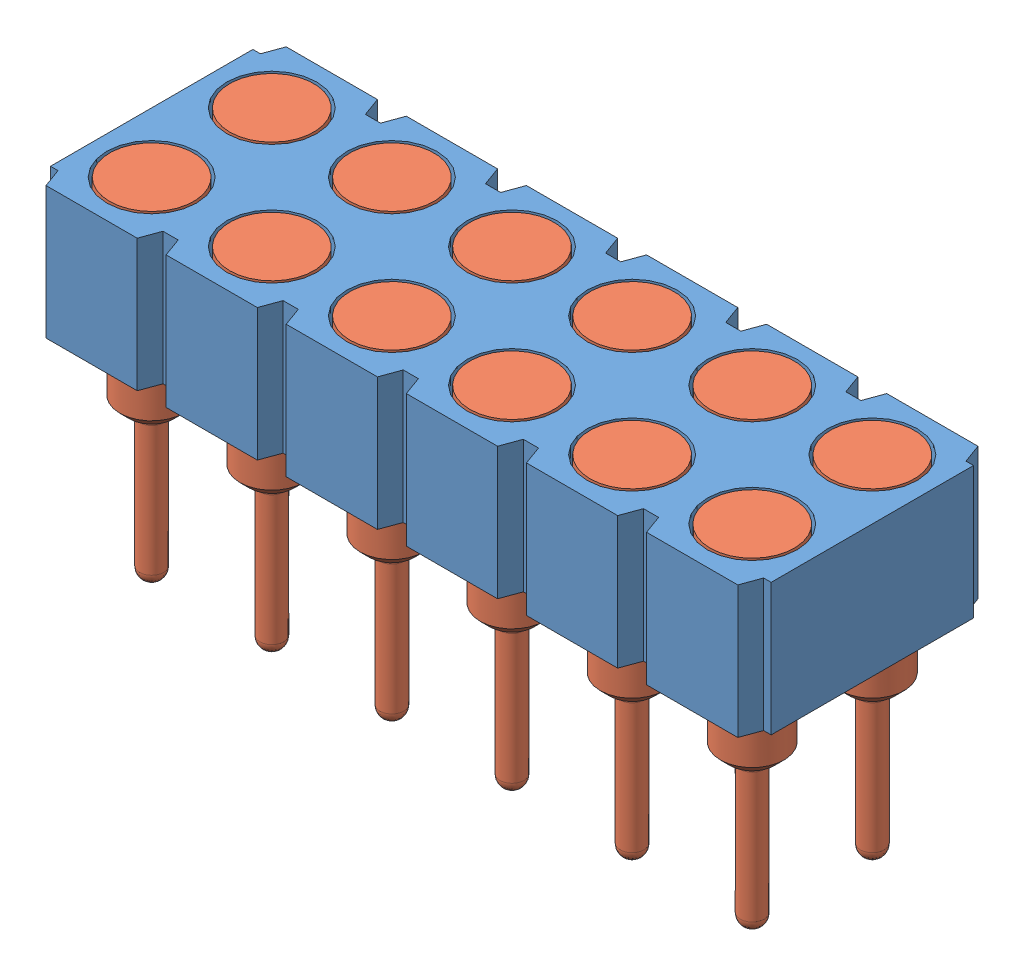
SolidWorks assembly mill-max-419-10-212-00-001000, configuration MillMaxsldprt2015419-XX-XXX-00-0010001210uGoldoverNickelPage14off. Lengths in mm.
Overall size (15.24 7.37 5.08).
13 component instances, 2 part files, 4 mates.
Components (placement in the parent):
- mill-max-419-10-212-00-001000_P4XX-21-010-00-000000-1: mill-max-419-10-212-00-001000_P4XX-21-010-00-000000 [P412-21-010-00-000000] at origin size (15.24 2.79 5.08)
- mill-max-419-10-212-00-001000_1942-1: mill-max-419-10-212-00-001000_1942 [Default] at (0.9644 0 -1.27) x (0 -1 0) z (0 0 1) size (7.37 1.78 1.78)
- mill-max-419-10-212-00-001000_1942-31: mill-max-419-10-212-00-001000_1942 [Default] at (0.9644 0 -3.81) x (0 -1 0) z (0 0 1) size (7.37 1.78 1.78)
- mill-max-419-10-212-00-001000_1942-32: mill-max-419-10-212-00-001000_1942 [Default] at (3.5044 0 -3.81) x (0 -1 0) z (0 0 1) size (7.37 1.78 1.78)
- mill-max-419-10-212-00-001000_1942-20: mill-max-419-10-212-00-001000_1942 [Default] at (3.5044 0 -1.27) x (0 -1 0) z (0 0 1) size (7.37 1.78 1.78)
- mill-max-419-10-212-00-001000_1942-33: mill-max-419-10-212-00-001000_1942 [Default] at (6.0444 0 -3.81) x (0 -1 0) z (0 0 1) size (7.37 1.78 1.78)
- mill-max-419-10-212-00-001000_1942-34: mill-max-419-10-212-00-001000_1942 [Default] at (8.5844 0 -3.81) x (0 -1 0) z (0 0 1) size (7.37 1.78 1.78)
- mill-max-419-10-212-00-001000_1942-35: mill-max-419-10-212-00-001000_1942 [Default] at (11.1244 0 -3.81) x (0 -1 0) z (0 0 1) size (7.37 1.78 1.78)
- mill-max-419-10-212-00-001000_1942-36: mill-max-419-10-212-00-001000_1942 [Default] at (13.6644 0 -3.81) x (0 -1 0) z (0 0 1) size (7.37 1.78 1.78)
- mill-max-419-10-212-00-001000_1942-27: mill-max-419-10-212-00-001000_1942 [Default] at (6.0444 0 -1.27) x (0 -1 0) z (0 0 1) size (7.37 1.78 1.78)
- mill-max-419-10-212-00-001000_1942-28: mill-max-419-10-212-00-001000_1942 [Default] at (8.5844 0 -1.27) x (0 -1 0) z (0 0 1) size (7.37 1.78 1.78)
- mill-max-419-10-212-00-001000_1942-29: mill-max-419-10-212-00-001000_1942 [Default] at (11.1244 0 -1.27) x (0 -1 0) z (0 0 1) size (7.37 1.78 1.78)
- mill-max-419-10-212-00-001000_1942-30: mill-max-419-10-212-00-001000_1942 [Default] at (13.6644 0 -1.27) x (0 -1 0) z (0 0 1) size (7.37 1.78 1.78)
Mates (geometry in assembly coordinates):
- Concentric1: concentric aligned: circle of mill-max-419-10-212-00-001000_1942-1; circle of mill-max-419-10-212-00-001000_P4XX-21-010-00-000000-1
- Coincident1: coincident aligned: plane of mill-max-419-10-212-00-001000_P4XX-21-010-00-000000-1 through (-0.1456 0 -4.68) normal (0 1 0); plane of mill-max-419-10-212-00-001000_1942-1 through (0.9644 0 -1.27) normal (0 1 0)
- Concentric2: concentric: circle of mill-max-419-10-212-00-001000_1942-31; circle of mill-max-419-10-212-00-001000_P4XX-21-010-00-000000-1
- Coincident2: coincident aligned: plane of mill-max-419-10-212-00-001000_P4XX-21-010-00-000000-1 through (-0.1456 0 -4.68) normal (0 1 0); plane of mill-max-419-10-212-00-001000_1942-31 through (0.9644 0 -3.81) normal (0 1 0)
